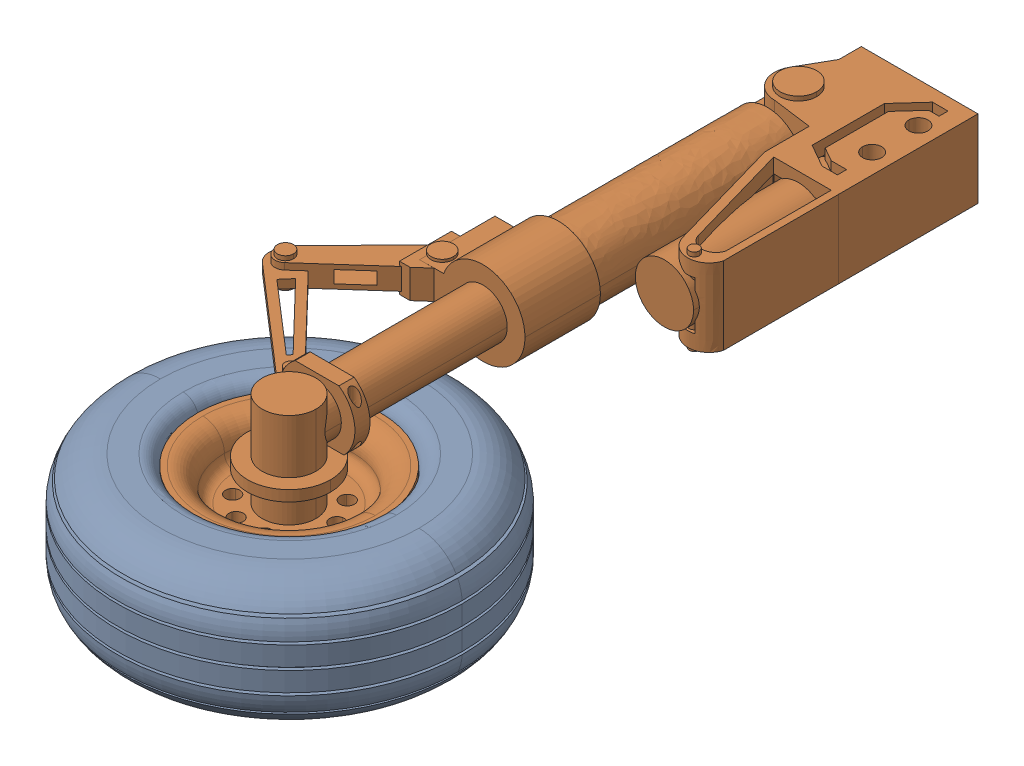
SolidWorks assembly MirrorLanding gear assembly, configuration Default. Lengths in mm.
Overall size (137.21 80.09 297.16).
2 component instances, 2 part files, 0 mates.
Components (placement in the parent):
- MirrorLanding gear tire-1: MirrorLanding gear tire [Default] at (41.2481 74.6537 -108.5035) size (137.21 51.51 137.21)
- MirrorLanging gear-1: MirrorLanging gear [Default] at (41.1897 73.9625 -108.2807) size (107.12 80.09 265.25)
